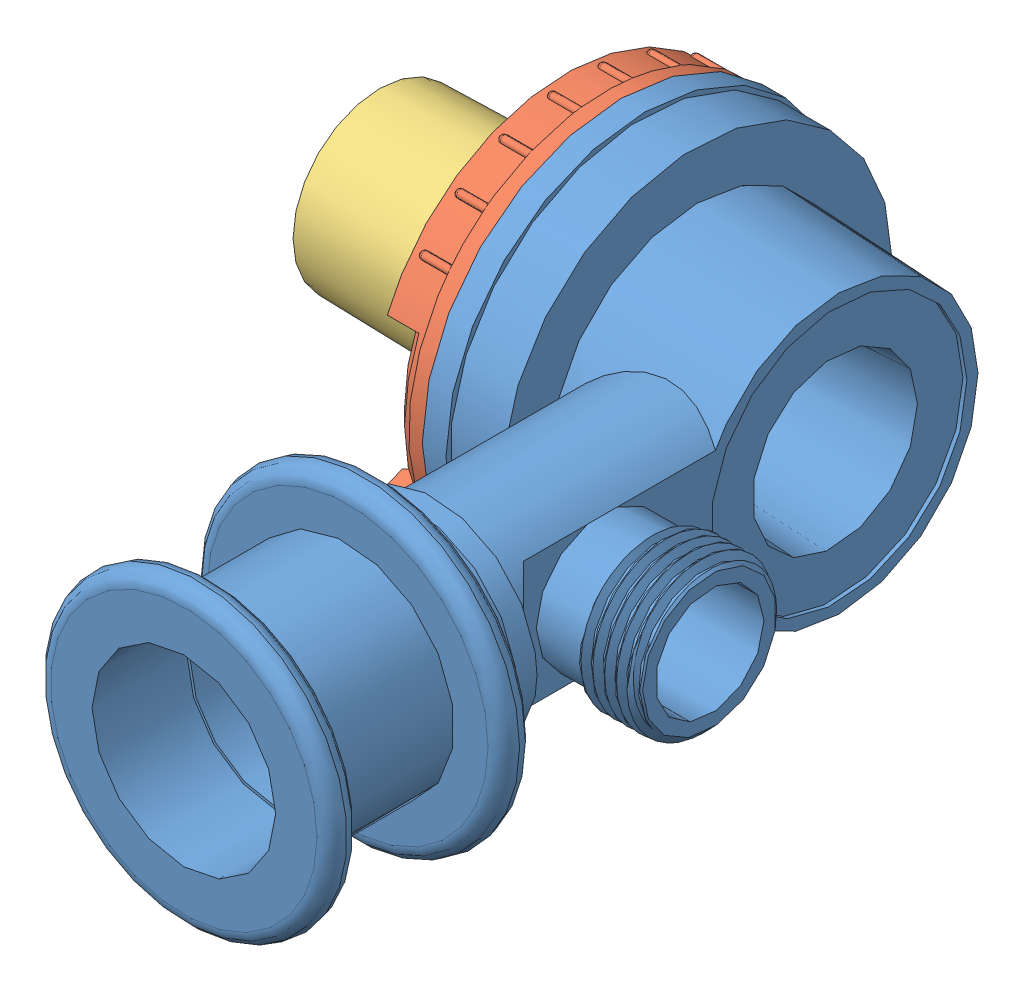
SolidWorks assembly Assy_Ambu-Bag_Outlet, configuration Default. Lengths in mm.
Overall size (72.2 65.3 107.95).
5 component instances, 5 part files, 9 mates.
Components (placement in the parent):
- Ambu-Bag_Outlet-1: Ambu-Bag_Outlet [Default] at origin size (42.06 50.5 100.55)
- Ambu-Bag_Outlet_Body_Connector-1: Ambu-Bag_Outlet_Body_Connector [Default] x (-1 0 0) z (0 -0.924225 -0.381849) size (13 50 50)
- Ambu-Bag_Outlet_Body_Connector_Pipe-1: Ambu-Bag_Outlet_Body_Connector_Pipe [Default] at (-36.15 0 0) size (35 30 30)
- Ambu-Bag_Outlet_Clip-1: Ambu-Bag_Outlet_Clip [Default] at (-13.5 0 0) x (1 0 0) z (0 -0.381849 0.924225) size (5 30.5 30.5)
- Ambu-Bag_Outlet_Diaphram-1: Ambu-Bag_Outlet_Diaphram [Default] at (2.6 0 0) x (-1 0 0) z (0 -1 0) size (16 43.5 43.5)
Mates (geometry in assembly coordinates):
- Coincident1: coincident anti-aligned: plane of Ambu-Bag_Outlet-1 through (-5.5 23 0) normal (-1 0 0); plane of Ambu-Bag_Outlet_Body_Connector-1 through (-5.5 8.9735 -21.7193) normal (1 0 0)
- Concentric1: concentric anti-aligned: circle of Ambu-Bag_Outlet-1; cylinder of Ambu-Bag_Outlet_Body_Connector-1 through (0 0 0) axis (1 0 0) radius 12.5
- Coincident2: coincident anti-aligned: plane of Ambu-Bag_Outlet_Body_Connector-1 through (-6.25 7.8852 -19.0852) normal (1 0 0); plane of Ambu-Bag_Outlet_Body_Connector_Pipe-1 through (-6.25 15 0) normal (-1 0 0)
- Concentric2: concentric anti-aligned: cylinder of Ambu-Bag_Outlet_Body_Connector-1 through (0 0 0) axis (1 0 0) radius 12.5; circle of Ambu-Bag_Outlet_Body_Connector_Pipe-1
- Coincident3: coincident anti-aligned: plane of Ambu-Bag_Outlet_Body_Connector-1 through (-8.5 7.7324 -18.7155) normal (-1 0 0); plane of Ambu-Bag_Outlet_Clip-1 through (-8.5 12.4936 5.1618) normal (1 0 0)
- Concentric3: concentric aligned: circle of Ambu-Bag_Outlet_Body_Connector_Pipe-1; cylinder of Ambu-Bag_Outlet_Clip-1 through (-13.5 0 0) axis (-1 0 0) radius 11.5
- Angle1: planar angle = 1.570796 rad aligned: plane of Ambu-Bag_Outlet_Diaphram-1 through (2.6 0 0) normal (0 0 -1)
- Concentric5: concentric aligned: cylinder of Ambu-Bag_Outlet-1 through (-1 0 0) axis (1 0 0) radius 17.0794; cylinder of Ambu-Bag_Outlet_Diaphram-1 through (2.6 0 0) axis (1 0 0) radius 19.05
- Coincident5: coincident anti-aligned: plane of Ambu-Bag_Outlet-1 through (2.6 18.75 0) normal (-1 0 0); plane of Ambu-Bag_Outlet_Diaphram-1 through (2.6 0 -18.75) normal (1 0 0)
